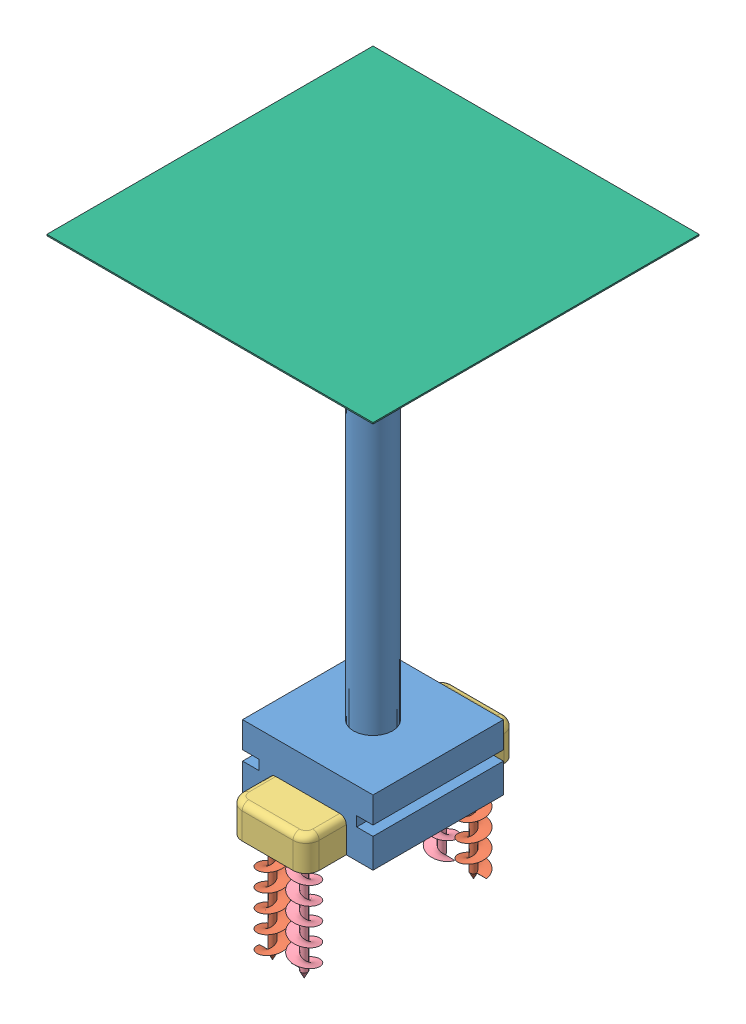
SolidWorks assembly pole, configuration Default. Lengths in mm.
Overall size (1000 1818.74 1000).
11 component instances, 6 part files, 11 mates.
Components (placement in the parent):
- pilon-1: pilon [Default] at (750.6878 634.4701 2074.8363) size (400 1200 400)
- fix-1: fix [Default] at (704.1878 324.4701 2336.3363) size (236 430 123)
  - screw - Copy-1: screw - Copy [Default] at origin size (83 330 83)
  - Part3^fix-1: Part3^fix [Default] at origin size (236 100 123) (virtual)
  - screw2 - Copy - Copy-1: screw2 - Copy - Copy [Default] at (97.0846 0 0) size (83 330 83)
- fix-2: fix [Default] at (797.1878 324.4701 1813.3363) x (-1 0 0) z (0 0 -1) size (236 430 123)
  - screw - Copy-1: screw - Copy [Default] at origin size (83 330 83)
  - Part3^fix-1: Part3^fix [Default] at origin size (236 100 123) (virtual)
  - screw2 - Copy - Copy-1: screw2 - Copy - Copy [Default] at (97.0846 0 0) size (83 330 83)
- pilon2-1: pilon2 [Default] at (750.6878 909.2097 2074.8363) x (-0.999521 0 0.03096) z (-0.03096 0 -0.999521) size (110 1000 110)
- cap-2: cap [Default] at (750.6878 1909.2097 2074.8363) size (1000 264 1000)
Mates (geometry in assembly coordinates):
- Coincident2: coincident: plane of pilon-1 through (950.6878 834.4701 2274.8363) normal (0 0 1); plane of fix-1/Part3^fix-1 through (632.6878 734.4701 2274.8363) normal (0 0 -1)
- Width1: width: plane of pilon-1 through (950.6878 834.4701 2274.8363) normal (1 0 0); plane of pilon-1 through (550.6878 834.4701 2274.8363) normal (-1 0 0); plane of fix-1/Part3^fix-1 through (868.6878 734.4701 2357.8363) normal (1 0 0); plane of fix-1/Part3^fix-1 through (632.6878 734.4701 2357.8363) normal (-1 0 0)
- Coincident3: coincident: plane of pilon-1 through (750.6878 634.4701 2074.8363) normal (0 -1 0); plane of fix-1/Part3^fix-1 through (828.6878 634.4701 2357.8363) normal (0 -1 0)
- Coincident4: coincident: plane of pilon-1 through (950.6878 834.4701 1874.8363) normal (0 0 -1); plane of fix-2/Part3^fix-1 through (868.6878 734.4701 1874.8363) normal (0 0 1)
- Width2: width: plane of pilon-1 through (950.6878 834.4701 2274.8363) normal (1 0 0); plane of pilon-1 through (550.6878 834.4701 2274.8363) normal (-1 0 0); plane of fix-2/Part3^fix-1 through (868.6878 734.4701 1791.8363) normal (1 0 0); plane of fix-2/Part3^fix-1 through (632.6878 734.4701 1791.8363) normal (-1 0 0)
- Coincident5: coincident: plane of pilon-1 through (750.6878 634.4701 2074.8363) normal (0 -1 0); plane of fix-2/Part3^fix-1 through (672.6878 634.4701 1791.8363) normal (0 -1 0)
- Concentric1: concentric: cylinder of pilon-1 through (750.6878 2834.4701 2074.8363) axis (0 -1 0) radius 50; cylinder of ? through (750.6878 2784.4701 2074.8363) axis (0 1 0) radius 45
- Coincident6: coincident: plane of pilon-1 through (750.6878 2834.4701 2074.8363) normal (0 1 0); plane of ? through (750.6878 2834.4701 2074.8363) normal (0 -1 0)
- Concentric2: concentric: cylinder of pilon-1 through (750.6878 1834.4701 2074.8363) axis (0 -1 0) radius 55; cylinder of pilon2-1 through (750.6878 1909.2097 2074.8363) axis (0 -1 0) radius 55
- Concentric3: concentric: cylinder of pilon2-1 through (750.6878 1909.2097 2074.8363) axis (0 -1 0) radius 50; cylinder of cap-2 through (750.6878 1859.2097 2074.8363) axis (0 1 0) radius 45
- Coincident7: coincident: plane of pilon2-1 through (750.6878 1909.2097 2074.8363) normal (0 1 0); plane of cap-2 through (750.6878 1909.2097 2074.8363) normal (0 -1 0)
